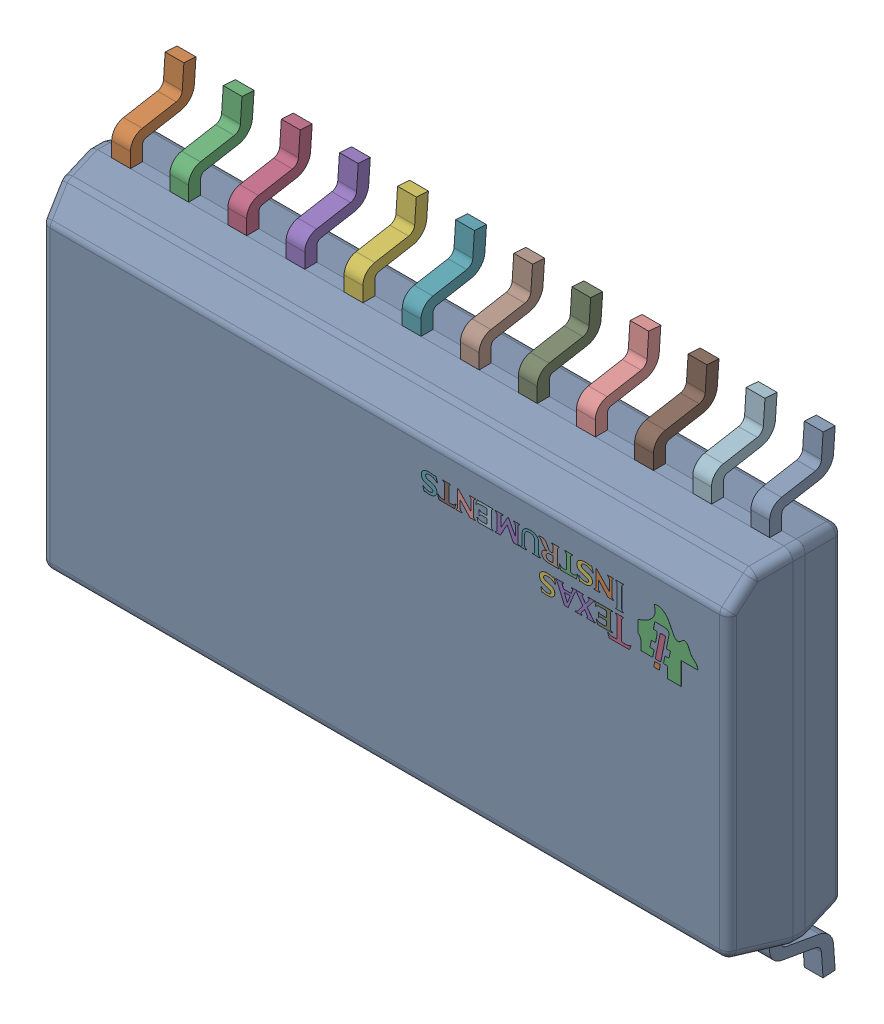
SolidWorks assembly U1, configuration Défaut. Lengths in mm.
Overall size (15.4 10.34 2.65).
28 component instances, 4 part files, 0 mates.
Components (placement in the parent):
- IC_Texas_Instruments_CD74HC4067M96_eec-1: IC_Texas_Instruments_CD74HC4067M96_eec [Défaut] at (-28.875 0 0) x (0 1 0) z (0 0 1) size (10.34 15.4 2.65)
  - BODY-SO-1: BODY-SO [Défaut] at (0 0 1.0825) x (0 1 0) z (1 0 0) size (15.4 2.45 7.5)
  - LEAD-SO-1: LEAD-SO [Défaut] at (4.315 6.985 0.25) x (0 1 0) z (1 0 0) size (0.41 1.43 1.42)
  - LEAD-SO-2: LEAD-SO [Défaut] at (4.315 5.715 0.25) x (0 1 0) z (1 0 0) size (0.41 1.43 1.42)
  - LEAD-SO-3: LEAD-SO [Défaut] at (4.315 4.445 0.25) x (0 1 0) z (1 0 0) size (0.41 1.43 1.42)
  - LEAD-SO-4: LEAD-SO [Défaut] at (4.315 3.175 0.25) x (0 1 0) z (1 0 0) size (0.41 1.43 1.42)
  - LEAD-SO-5: LEAD-SO [Défaut] at (4.315 1.905 0.25) x (0 1 0) z (1 0 0) size (0.41 1.43 1.42)
  - LEAD-SO-6: LEAD-SO [Défaut] at (4.315 0.635 0.25) x (0 1 0) z (1 0 0) size (0.41 1.43 1.42)
  - LEAD-SO-7: LEAD-SO [Défaut] at (4.315 -0.635 0.25) x (0 1 0) z (1 0 0) size (0.41 1.43 1.42)
  - LEAD-SO-8: LEAD-SO [Défaut] at (4.315 -1.905 0.25) x (0 1 0) z (1 0 0) size (0.41 1.43 1.42)
  - LEAD-SO-9: LEAD-SO [Défaut] at (4.315 -3.175 0.25) x (0 1 0) z (1 0 0) size (0.41 1.43 1.42)
  - LEAD-SO-10: LEAD-SO [Défaut] at (4.315 -4.445 0.25) x (0 1 0) z (1 0 0) size (0.41 1.43 1.42)
  - LEAD-SO-11: LEAD-SO [Défaut] at (4.315 -5.715 0.25) x (0 1 0) z (1 0 0) size (0.41 1.43 1.42)
  - LEAD-SO-12: LEAD-SO [Défaut] at (4.315 -6.985 0.25) x (0 1 0) z (1 0 0) size (0.41 1.43 1.42)
  - LEAD-SO-13: LEAD-SO [Défaut] at (-4.315 6.985 0.25) x (0 -1 0) z (-1 0 0) size (0.41 1.43 1.42)
  - LEAD-SO-14: LEAD-SO [Défaut] at (-4.315 5.715 0.25) x (0 -1 0) z (-1 0 0) size (0.41 1.43 1.42)
  - LEAD-SO-15: LEAD-SO [Défaut] at (-4.315 4.445 0.25) x (0 -1 0) z (-1 0 0) size (0.41 1.43 1.42)
  - LEAD-SO-16: LEAD-SO [Défaut] at (-4.315 3.175 0.25) x (0 -1 0) z (-1 0 0) size (0.41 1.43 1.42)
  - LEAD-SO-17: LEAD-SO [Défaut] at (-4.315 1.905 0.25) x (0 -1 0) z (-1 0 0) size (0.41 1.43 1.42)
  - LEAD-SO-18: LEAD-SO [Défaut] at (-4.315 0.635 0.25) x (0 -1 0) z (-1 0 0) size (0.41 1.43 1.42)
  - LEAD-SO-19: LEAD-SO [Défaut] at (-4.315 -0.635 0.25) x (0 -1 0) z (-1 0 0) size (0.41 1.43 1.42)
  - LEAD-SO-20: LEAD-SO [Défaut] at (-4.315 -1.905 0.25) x (0 -1 0) z (-1 0 0) size (0.41 1.43 1.42)
  - LEAD-SO-21: LEAD-SO [Défaut] at (-4.315 -3.175 0.25) x (0 -1 0) z (-1 0 0) size (0.41 1.43 1.42)
  - LEAD-SO-22: LEAD-SO [Défaut] at (-4.315 -4.445 0.25) x (0 -1 0) z (-1 0 0) size (0.41 1.43 1.42)
  - LEAD-SO-23: LEAD-SO [Défaut] at (-4.315 -5.715 0.25) x (0 -1 0) z (-1 0 0) size (0.41 1.43 1.42)
  - LEAD-SO-24: LEAD-SO [Défaut] at (-4.315 -6.985 0.25) x (0 -1 0) z (-1 0 0) size (0.41 1.43 1.42)
  - Texas Logo Yury-1: Texas Logo Yury [Défaut] at (2.174 -7.1221 2.551) x (0 1 0) z (0 0 1) size (1.32 1.29 0.11)
  - Texas Logo Yury - Copy-1: Texas Logo Yury - Copy [Défaut] at (2.0641 -7.1534 2.551) x (0 1 0) z (0 0 1) size (4.61 1.2 0.1)
